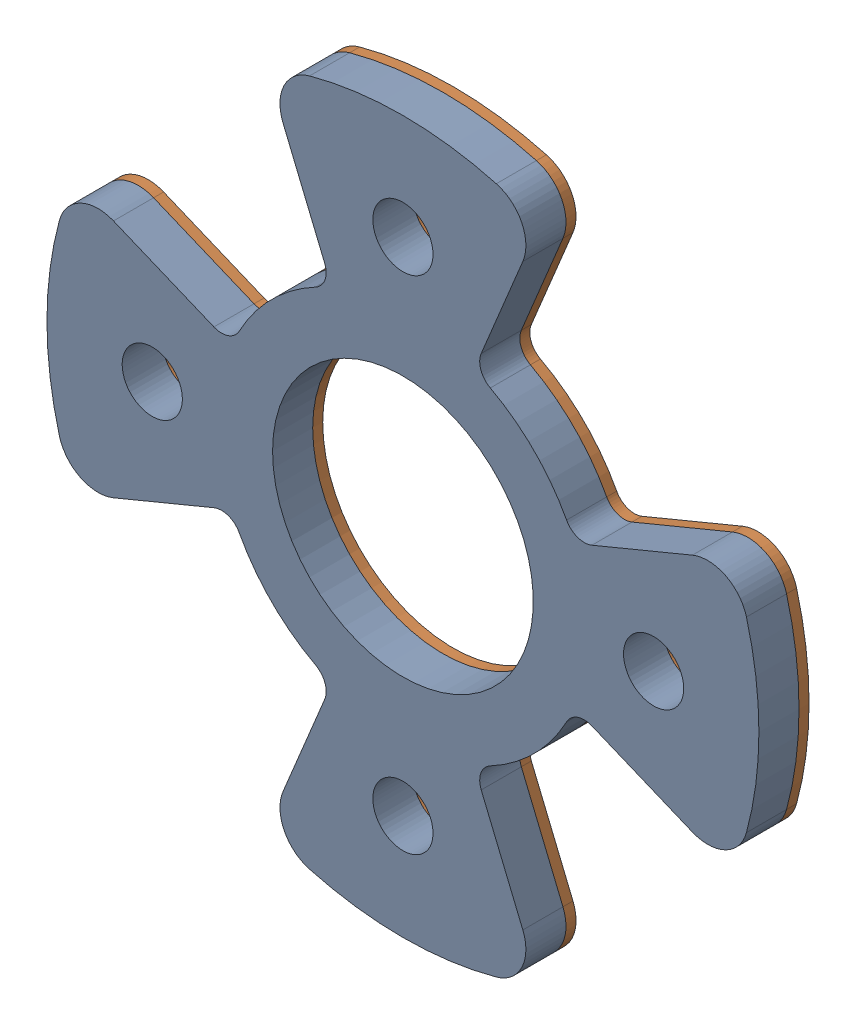
SolidWorks assembly Spacers, configuration Default. Lengths in mm.
Overall size (35.5 35.5 2.5).
2 component instances, 2 part files, 0 mates.
Components (placement in the parent):
- PCB-1: PCB [Default] at (-11.099 -71.9658 -4) size (35.5 35.5 2)
- Steel-1: Steel [Default] at (-11.099 -71.9658 -4.5) size (35.5 35.5 0.5)
